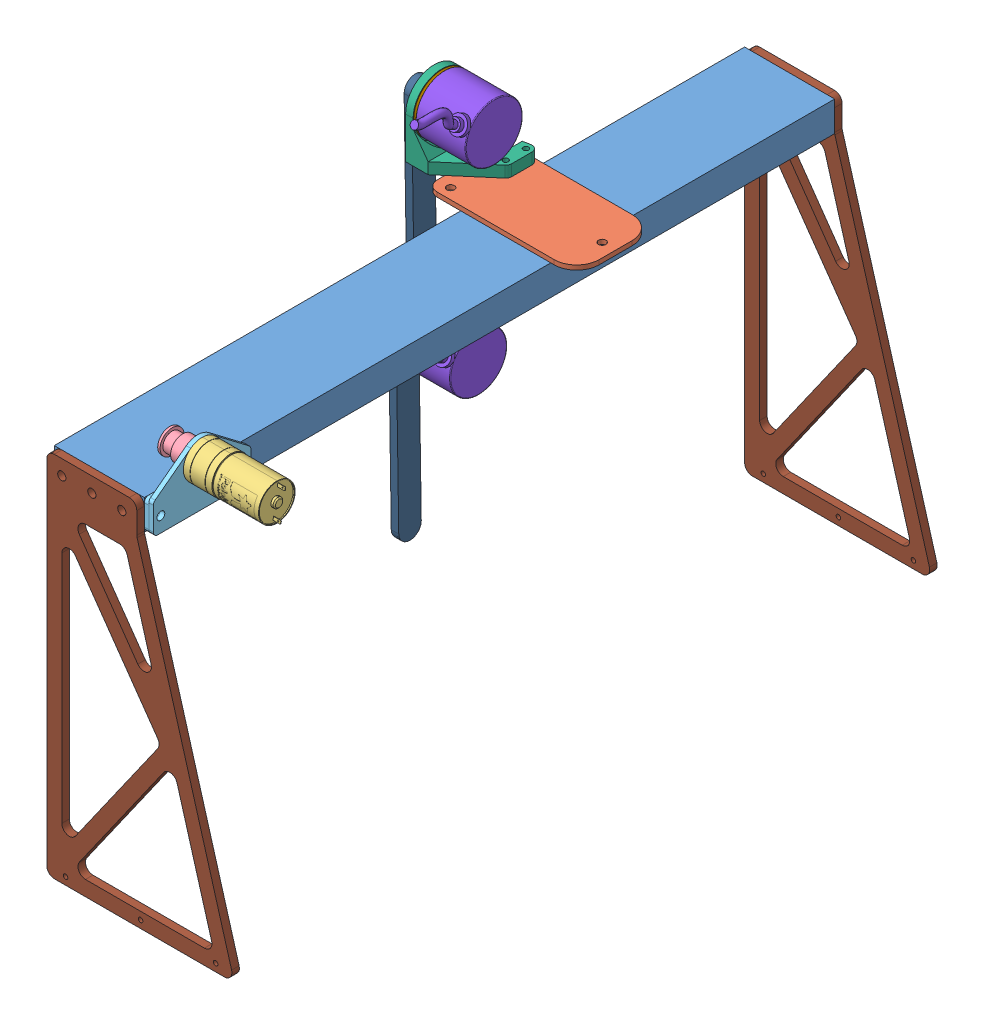
SolidWorks assembly doublePend, configuration Default. Lengths in mm.
Overall size (189.35 321.53 470).
21 component instances, 11 part files, 32 mates.
Components (placement in the parent):
- 6020beam-1: 6020beam [Default] at origin size (60 20 460)
- slide-plate-1: slide-plate [Default] at (0 12.75 -64.1095) size (100 3 52)
- 25d-metal-gearmotor-20.4-1: 25d-metal-gearmotor-20.4 [Default] at (54.375 49.8684 196.8635) x (0 -0.999787 0.020616) z (-1 0 0) size (25 25 66.5)
- gt2-4mm-20t-pulley-1: gt2-4mm-20t-pulley [Default] at (30.42 19 197.5) x (0 -0.950086 -0.311988) z (0 0.311988 -0.950086) size (16 16 16)
- motormount-1: motormount [Default] at (36 19 197.5) x (0 0 1) z (0 -1 0) size (65 3 41.5)
- motormount-2: motormount [spacer] at (33 19 197.5) x (0 0 1) z (0 -1 0) size (65 3 20)
- armMount-1: armMount [Default] at (-71 43.25 -64.1095) x (0 0 -1) z (1 0 0) size (44.2 46.5 44)
- CALT ES38 6mm Solid Shaft NPN AB 2 Phase 8-24V Incremental Optical Rotary Encoder 100 200 360 400 500 600 1000 PPR-1: CALT ES38 6mm Solid Shaft NPN AB 2 Phase 8-24V Incremental Optical Rotary Encoder 100 200 360 400 500 600 1000 PPR [Default] at (-31 43.25 -64.1095) x (0 -0.866025 0.5) z (-1 0 0) size (38 72.66 52.55)
  - CALT ES38 6mm Solid Shaft NPN AB 2 Phase 8-24V Incremental Optical Rotary Encoder 100 200 360 400 500 600 1000 PPR.step-1: CALT ES38 6mm Solid Shaft NPN AB 2 Phase 8-24V Incremental Optical Rotary Encoder 100 200 360 400 500 600 1000 PPR.step [Default] at origin size (38 72.66 52.55)
    - encoder_shaft.step-1: encoder_shaft.step [Default] x (-0.906308 -0.422618 0) z (0 0 1) size (6 6 12.5)
    - encoder_body.step-1: encoder_body.step [Default] at origin size (38 72.66 33.05)
    - encode_top.step-1: encode_top.step [Default] at origin size (38 38 7)
- arms-5: arms [Default] at (-83.5 -96.734 -66.2246) x (0 0.999886 0.015108) z (0 0.015108 -0.999886) size (160 5 31.11)
- CALT ES38 6mm Solid Shaft NPN AB 2 Phase 8-24V Incremental Optical Rotary Encoder 100 200 360 400 500 600 1000 PPR-2: CALT ES38 6mm Solid Shaft NPN AB 2 Phase 8-24V Incremental Optical Rotary Encoder 100 200 360 400 500 600 1000 PPR [Default] at (-43.5 -96.734 -66.2246) x (0 -0.87348 0.486859) z (-1 0 0) size (38 72.66 52.55)
  - CALT ES38 6mm Solid Shaft NPN AB 2 Phase 8-24V Incremental Optical Rotary Encoder 100 200 360 400 500 600 1000 PPR.step-1: CALT ES38 6mm Solid Shaft NPN AB 2 Phase 8-24V Incremental Optical Rotary Encoder 100 200 360 400 500 600 1000 PPR.step [Default] at origin size (38 72.66 52.55)
    - encoder_shaft.step-1: encoder_shaft.step [Default] x (-0.906308 -0.422618 0) z (0 0 1) size (6 6 12.5)
    - encoder_body.step-1: encoder_body.step [Default] at origin size (38 72.66 33.05)
    - encode_top.step-1: encode_top.step [Default] at origin size (38 38 7)
- arms-6: arms [secondArm] at (-96 -216.7203 -68.0376) x (0 0.999886 0.015108) z (0 0.015108 -0.999886) size (135 5 15)
- stand-1: stand [Default] at (0 0 230) x (0 0 1) z (-1 0 0) size (5 245 123.35)
- stand-2: stand [Default] at (0 0 -235) x (0 0 1) z (-1 0 0) size (5 245 123.35)
Mates (geometry in assembly coordinates):
- Distance1: distance = 5.75 mm aligned: plane of slide-plate-1 through (0 15.75 -64.1095) normal (0 1 0); plane of 6020beam-1 through (-30 10 230) normal (0 1 0)
- Coincident2: coincident aligned: plane of slide-plate-1 through (0 12.75 -64.1095) normal (1 0 0)
- Coincident11: coincident anti-aligned: cylinder of 25d-metal-gearmotor-20.4-1 through (36 19 197.5) axis (-1 0 0) radius 2; circle of gt2-4mm-20t-pulley-1
- Distance3: distance = 46 mm anti-aligned: plane of gt2-4mm-20t-pulley-1 through (16 24.805 199.4062) normal (1 0 0); plane of 6020beam-1 through (-30 -10 230) normal (-1 0 0)
- Coincident13: coincident aligned: plane of 6020beam-1 through (-30 -10 230) normal (0 -1 0); plane of motormount-1 through (33 -10 197.5) normal (0 -1 0)
- Parallel1: parallel aligned: plane of 25d-metal-gearmotor-20.4-1 through (36 19 197.5) normal (-1 0 0); plane of motormount-1 through (33 19 197.5) normal (-1 0 0)
- Concentric9: concentric anti-aligned: cylinder of 25d-metal-gearmotor-20.4-1 through (55 19 197.5) axis (-1 0 0) radius 12.5; cylinder of motormount-1 through (33 19 197.5) axis (1 0 0) radius 12.5
- Coincident17: coincident aligned: plane of 6020beam-1 through (0 0 230) normal (0 0 1); plane of motormount-1 through (33 19 230) normal (0 0 1)
- Coincident18: coincident anti-aligned: plane of 25d-metal-gearmotor-20.4-1 through (36 19 197.5) normal (-1 0 0); plane of motormount-1 through (36 19 197.5) normal (1 0 0)
- Coincident19: coincident anti-aligned: plane of 6020beam-1 through (30 -10 230) normal (1 0 0); plane of motormount-2 through (30 19 197.5) normal (-1 0 0)
- Coincident20: coincident anti-aligned: plane of motormount-1 through (33 19 197.5) normal (-1 0 0); plane of motormount-2 through (33 19 197.5) normal (1 0 0)
- Concentric10: concentric aligned: cylinder of motormount-1 through (36 0 225) axis (1 0 0) radius 2.65; cylinder of motormount-2 through (33 0 225) axis (1 0 0) radius 2.65
- Concentric11: concentric aligned: cylinder of motormount-1 through (36 0 170) axis (1 0 0) radius 2.65; cylinder of motormount-2 through (33 0 170) axis (1 0 0) radius 2.65
- Coincident21: coincident anti-aligned: plane of slide-plate-1 through (0 15.75 -64.1095) normal (0 1 0); plane of armMount-1 through (-66 15.75 -64.1095) normal (0 -1 0)
- Concentric12: concentric aligned: cylinder of slide-plate-1 through (-31 15.75 -85.3095) axis (0 -1 0) radius 2; cylinder of armMount-1 through (-31 15.75 -85.3095) axis (0 -1 0) radius 1.8
- Concentric14: concentric anti-aligned: circle of slide-plate-1; cylinder of armMount-1 through (-31 15.75 -71.8095) axis (0 -1 0) radius 1.8
- Coincident22: coincident anti-aligned: plane of armMount-1 through (-66 43.25 -64.1095) normal (1 0 0); plane of CALT ES38 6mm Solid Shaft NPN AB 2 Phase 8-24V Incremental Optical Rotary Encoder 100 200 360 400 500 600 1000 PPR-1/CALT ES38 6mm Solid Shaft NPN AB 2 Phase 8-24V Incremental Optical Rotary Encoder 100 200 360 400 500 600 1000 PPR.step-1/encode_top.step-1 through (-66 43.25 -64.1095) normal (-1 0 0)
- Concentric15: concentric anti-aligned: cylinder of armMount-1 through (-66 43.25 -64.1095) axis (-1 0 0) radius 10.25; cylinder of CALT ES38 6mm Solid Shaft NPN AB 2 Phase 8-24V Incremental Optical Rotary Encoder 100 200 360 400 500 600 1000 PPR-1/CALT ES38 6mm Solid Shaft NPN AB 2 Phase 8-24V Incremental Optical Rotary Encoder 100 200 360 400 500 600 1000 PPR.step-1/encode_top.step-1 through (-71 43.25 -64.1095) axis (1 0 0) radius 10
- Concentric16: concentric anti-aligned: cylinder of armMount-1 through (-66 57.75 -64.1095) axis (1 0 0) radius 1.8; cylinder of CALT ES38 6mm Solid Shaft NPN AB 2 Phase 8-24V Incremental Optical Rotary Encoder 100 200 360 400 500 600 1000 PPR-1/CALT ES38 6mm Solid Shaft NPN AB 2 Phase 8-24V Incremental Optical Rotary Encoder 100 200 360 400 500 600 1000 PPR.step-1/encode_top.step-1 through (-56 57.75 -64.1095) axis (-1 0 0) radius 1.5
- Concentric17: concentric anti-aligned: cylinder of CALT ES38 6mm Solid Shaft NPN AB 2 Phase 8-24V Incremental Optical Rotary Encoder 100 200 360 400 500 600 1000 PPR-1/CALT ES38 6mm Solid Shaft NPN AB 2 Phase 8-24V Incremental Optical Rotary Encoder 100 200 360 400 500 600 1000 PPR.step-1/encoder_shaft.step-1 through (-83.5 43.25 -64.1095) axis (1 0 0) radius 3; cylinder of arms-5 through (-78.5 43.25 -64.1095) axis (-1 0 0) radius 3
- Coincident23: coincident aligned: plane of CALT ES38 6mm Solid Shaft NPN AB 2 Phase 8-24V Incremental Optical Rotary Encoder 100 200 360 400 500 600 1000 PPR-1/CALT ES38 6mm Solid Shaft NPN AB 2 Phase 8-24V Incremental Optical Rotary Encoder 100 200 360 400 500 600 1000 PPR.step-1/encoder_shaft.step-1 through (-83.5 43.25 -64.1095) normal (-1 0 0); plane of arms-5 through (-83.5 -96.734 -66.2246) normal (-1 0 0)
- Coincident24: coincident anti-aligned: plane of arms-5 through (-78.5 -96.734 -66.2246) normal (1 0 0); plane of CALT ES38 6mm Solid Shaft NPN AB 2 Phase 8-24V Incremental Optical Rotary Encoder 100 200 360 400 500 600 1000 PPR-2/CALT ES38 6mm Solid Shaft NPN AB 2 Phase 8-24V Incremental Optical Rotary Encoder 100 200 360 400 500 600 1000 PPR.step-1/encode_top.step-1 through (-78.5 -96.734 -66.2246) normal (-1 0 0)
- Concentric18: concentric anti-aligned: cylinder of arms-5 through (-78.5 -103.7935 -78.8901) axis (1 0 0) radius 1.7; cylinder of CALT ES38 6mm Solid Shaft NPN AB 2 Phase 8-24V Incremental Optical Rotary Encoder 100 200 360 400 500 600 1000 PPR-2/CALT ES38 6mm Solid Shaft NPN AB 2 Phase 8-24V Incremental Optical Rotary Encoder 100 200 360 400 500 600 1000 PPR.step-1/encode_top.step-1 through (-68.5 -103.7935 -78.8901) axis (-1 0 0) radius 1.5
- Concentric19: concentric anti-aligned: cylinder of arms-5 through (-78.5 -96.734 -66.2246) axis (-1 0 0) radius 10; cylinder of CALT ES38 6mm Solid Shaft NPN AB 2 Phase 8-24V Incremental Optical Rotary Encoder 100 200 360 400 500 600 1000 PPR-2/CALT ES38 6mm Solid Shaft NPN AB 2 Phase 8-24V Incremental Optical Rotary Encoder 100 200 360 400 500 600 1000 PPR.step-1/encode_top.step-1 through (-83.5 -96.734 -66.2246) axis (1 0 0) radius 10
- Concentric20: concentric anti-aligned: cylinder of CALT ES38 6mm Solid Shaft NPN AB 2 Phase 8-24V Incremental Optical Rotary Encoder 100 200 360 400 500 600 1000 PPR-2/CALT ES38 6mm Solid Shaft NPN AB 2 Phase 8-24V Incremental Optical Rotary Encoder 100 200 360 400 500 600 1000 PPR.step-1/encoder_shaft.step-1 through (-96 -96.734 -66.2246) axis (1 0 0) radius 3; cylinder of arms-6 through (-91 -96.734 -66.2246) axis (-1 0 0) radius 3
- Coincident25: coincident aligned: plane of CALT ES38 6mm Solid Shaft NPN AB 2 Phase 8-24V Incremental Optical Rotary Encoder 100 200 360 400 500 600 1000 PPR-2/CALT ES38 6mm Solid Shaft NPN AB 2 Phase 8-24V Incremental Optical Rotary Encoder 100 200 360 400 500 600 1000 PPR.step-1/encoder_shaft.step-1 through (-96 -96.734 -66.2246) normal (-1 0 0); plane of arms-6 through (-96 -216.7203 -68.0376) normal (-1 0 0)
- Coincident26: coincident anti-aligned: plane of 6020beam-1 through (0 0 230) normal (0 0 1); plane of stand-1 through (0 0 230) normal (0 0 -1)
- Coincident27: coincident aligned: plane of 6020beam-1 through (-30 10 230) normal (0 1 0); plane of stand-1 through (0 10 235) normal (0 1 0)
- Coincident28: coincident aligned: plane of 6020beam-1 through (-30 -10 230) normal (-1 0 0); plane of stand-1 through (-30 0 235) normal (-1 0 0)
- Coincident29: coincident anti-aligned: plane of 6020beam-1 through (0 0 -230) normal (0 0 -1); plane of stand-2 through (0 0 -230) normal (0 0 1)
- Coincident30: coincident aligned: plane of 6020beam-1 through (-30 -10 230) normal (-1 0 0); plane of stand-2 through (-30 0 -230) normal (-1 0 0)
- Coincident31: coincident aligned: plane of 6020beam-1 through (-30 10 230) normal (0 1 0); plane of stand-2 through (0 10 -230) normal (0 1 0)
